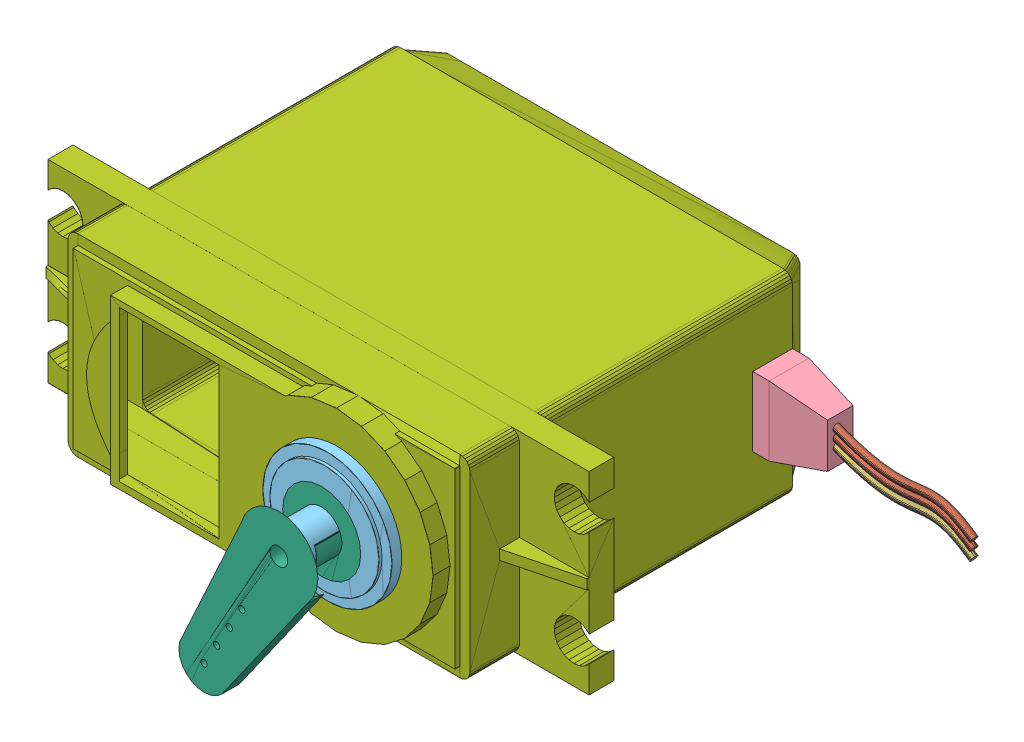
SolidWorks assembly Servo_HITEC_HS645MG, configuration Standard. Lengths in mm.
Overall size (1737.81 803.79 1114.29).
18 component instances, 8 part files, 0 mates.
Components (placement in the parent):
- Groupe_5-1: Groupe_5 [Standard] at origin size (1737.81 803.79 1114.29)
  - Groupe_6-1: Groupe_6 [Standard] at (231.2826 -91.8146 -539.1957) size (90.82 90.82 35.9)
    - Groupe_7-1: Groupe_7 [Standard] at origin size (90.82 90.82 35.9)
  - Groupe_6-2: Groupe_6 [Standard] at (231.2826 243.4654 -539.1957) size (90.82 90.82 35.9)
    - Groupe_7-1: Groupe_7 [Standard] at origin size (90.82 90.82 35.9)
  - Groupe_4-1: Groupe_4 [Standard] at (603.3792 69.1313 -424.1632) x (0 0 -1) z (1 0 0) size (101.7 178.59 531.1)
    - Groupe_8-1: Groupe_8 [Standard] at (-10.9872 -23.8269 84.5461) x (0 1 0) z (-1 0 0) size (130.89 361.96 18.8)
      - Groupe_8-1-1: Groupe_8-1 [Standard] at origin size (109.27 361.96 18.8)
      - Groupe_8-2-1: Groupe_8-2 [Standard] at origin size (88.6 361.96 18.8)
    - Groupe_8-2: Groupe_8 [Standard] at (-10.9872 -23.8269 84.5461) x (0 1 0) z (-1 0 0) size (130.89 361.96 18.8)
    - Groupe_4-1: Groupe_4 [Standard] at origin size (101.7 177.9 175.36)
  - Groupe_1-1: Groupe_1 [Standard] at (54.7631 76.0827 474.1397) size (330.2 330.2 134.62)
  - Groupe_6-3: Groupe_6 [Standard] at (-586.5974 243.4654 -539.1957) size (90.82 90.82 35.9)
    - Groupe_7-1: Groupe_7 [Standard] at origin size (90.82 90.82 35.9)
  - Groupe_6-4: Groupe_6 [Standard] at (-586.5974 -91.8146 -539.1957) size (90.82 90.82 35.9)
    - Groupe_7-1: Groupe_7 [Standard] at origin size (90.82 90.82 35.9)
  - Group_5-1: Group_5 [Standard] at (-31.4317 -78.1778 502.3083) x (0.866859 -0.498554 0) z (0 0 1) size (230.22 579.89 109.68)
  - Groupe_5-1: Groupe_5 [Standard] at origin size (1384.82 652.46 957.99)
